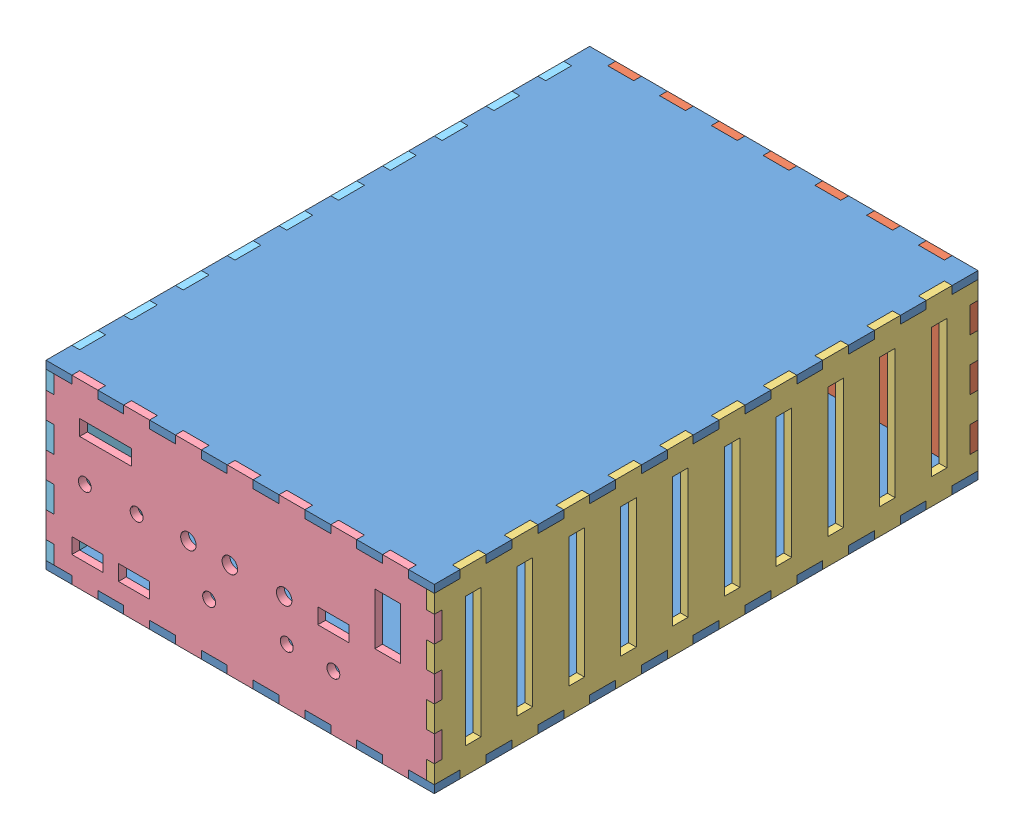
SolidWorks assembly Assem2, configuration Default. Lengths in mm.
Overall size (150 70 210).
6 component instances, 5 part files, 13 mates.
Components (placement in the parent):
- Part2-1: Part2 [Default] at (18.2052 84.5739 50.54) size (150 3 210)
- Part1-2: Part1 [Default] at (18.2052 52.5739 -54.46) size (150 70 3)
- Part3-1: Part3 [Default] at (90.2052 52.5739 50.54) size (3 70 210)
- Part2-3: Part2 [Default] at (18.2052 17.5739 50.54) size (150 3 210)
- Part11-1: Part11 [Default] at (18.2052 52.5739 152.54) size (150 70 3)
- Part33-1: Part33 [Default] at (-56.7948 52.5739 50.54) size (3 70 210)
Mates (geometry in assembly coordinates):
- Coincident9: coincident aligned: plane of Part2-1 through (18.2052 87.5739 50.54) normal (0 1 0); plane of Part1-2 through (-56.7948 87.5739 -51.46) normal (0 1 0)
- Coincident10: coincident aligned: plane of Part2-1 through (-56.7948 87.5739 155.54) normal (-1 0 0); plane of Part1-2 through (-56.7948 87.5739 -51.46) normal (-1 0 0)
- Coincident11: coincident aligned: plane of Part2-1 through (-56.7948 87.5739 -54.46) normal (0 0 -1); plane of Part1-2 through (18.2052 52.5739 -54.46) normal (0 0 -1)
- Coincident15: coincident aligned: plane of Part1-2 through (18.2052 52.5739 -54.46) normal (0 0 -1); plane of Part3-1 through (93.2052 17.5739 -54.46) normal (0 0 -1)
- Coincident16: coincident aligned: plane of Part2-1 through (18.2052 87.5739 50.54) normal (0 1 0); plane of Part3-1 through (93.2052 87.5739 155.54) normal (0 1 0)
- Coincident17: coincident anti-aligned: plane of Part1-2 through (90.2052 57.5739 -54.46) normal (1 0 0); plane of Part3-1 through (90.2052 52.5739 50.54) normal (-1 0 0)
- Coincident22: coincident aligned: plane of Part3-1 through (93.2052 52.5739 50.54) normal (1 0 0); plane of Part2-3 through (93.2052 20.5739 155.54) normal (1 0 0)
- Coincident27: coincident aligned: plane of Part2-1 through (-56.7948 87.5739 155.54) normal (0 0 1); plane of Part11-1 through (18.2052 52.5739 155.54) normal (0 0 1)
- Coincident28: coincident aligned: plane of Part2-1 through (18.2052 87.5739 50.54) normal (0 1 0); plane of Part11-1 through (-56.7948 87.5739 155.54) normal (0 1 0)
- Coincident30: coincident aligned: plane of Part3-1 through (93.2052 52.5739 50.54) normal (1 0 0); plane of Part11-1 through (93.2052 87.5739 155.54) normal (1 0 0)
- Coincident31: coincident aligned: plane of Part2-1 through (18.2052 87.5739 50.54) normal (0 1 0); plane of Part33-1 through (-53.7948 87.5739 155.54) normal (0 1 0)
- Coincident32: coincident aligned: plane of Part11-1 through (18.2052 52.5739 155.54) normal (0 0 1); plane of Part33-1 through (-53.7948 17.5739 155.54) normal (0 0 1)
- Coincident33: coincident aligned: plane of Part2-3 through (-56.7948 20.5739 155.54) normal (-1 0 0); plane of Part33-1 through (-56.7948 52.5739 50.54) normal (-1 0 0)
